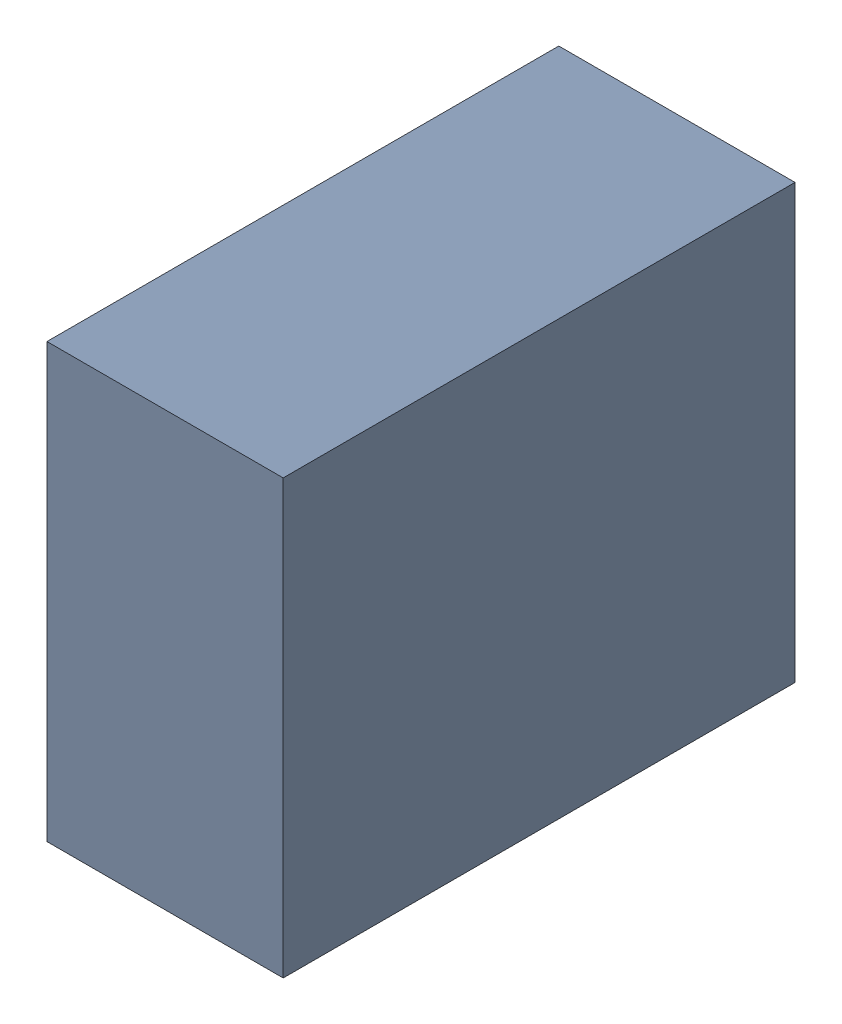
SolidWorks assembly C1, configuration Standard. Lengths in mm.
Overall size (0.6 1.1 1.3).
2 component instances, 1 part files, 0 mates.
Components (placement in the parent):
- 885542376-1: 885542376 [Standard] at (-3.55 13 0) size (0.6 1.1 1.3)
  - Extruded_25-1: Extruded_25 [Standard] at origin size (0.6 1.1 1.3)
